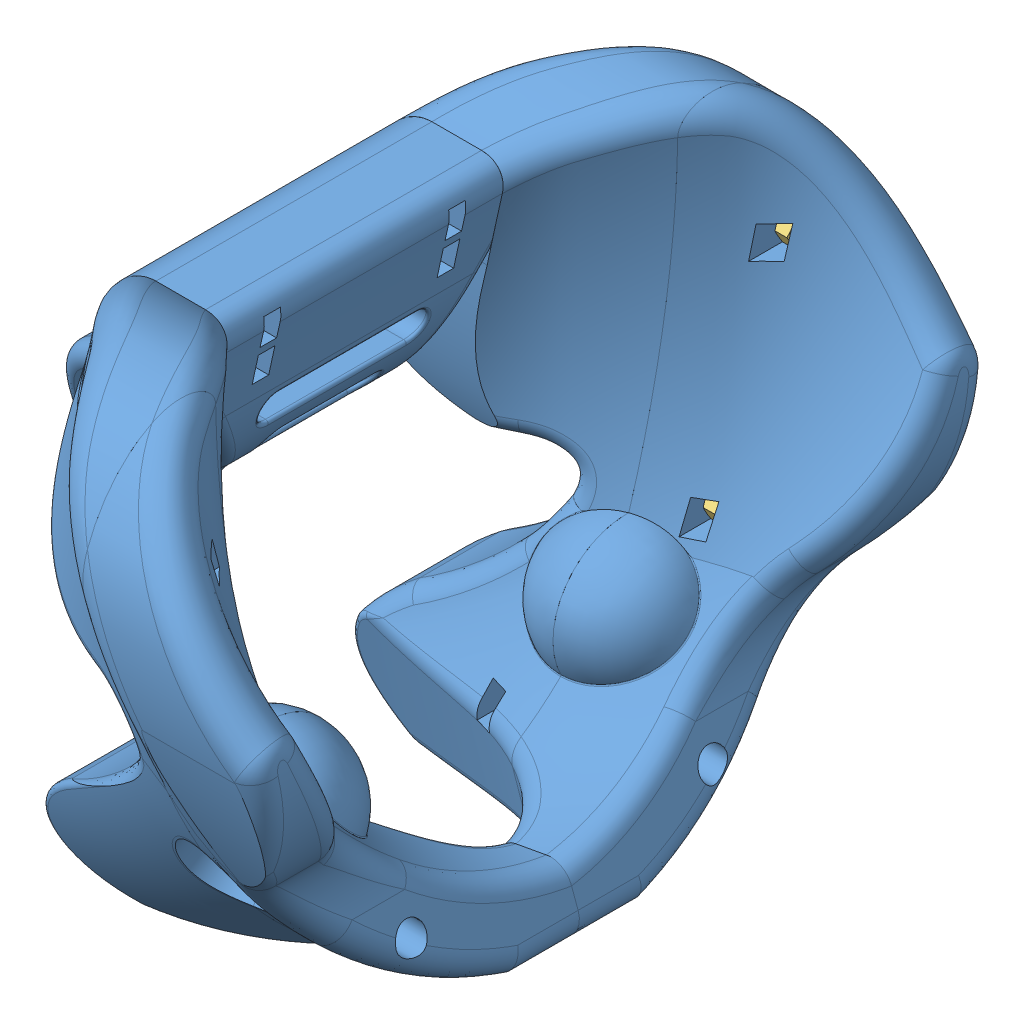
SolidWorks assembly 02_03_Pelvis_Assembly, configuration Default. Lengths in mm.
Overall size (197.88 220.17 282.18).
23 component instances, 3 part files, 55 mates.
Components (placement in the parent):
- 02_01_Pelvis-1: 02_01_Pelvis [Default] at origin size (197.88 220.17 282.18)
- 91239A330_CLASS 10.9 STL BUTTON-HEAD SOCKET CAP SCREW-1: 91239A330_CLASS 10.9 STL BUTTON-HEAD SOCKET CAP SCREW [91239A330] at (-121.884 56.6312 66.8) size (10.5 10.5 38.95)
- 91239A330_CLASS 10.9 STL BUTTON-HEAD SOCKET CAP SCREW-2: 91239A330_CLASS 10.9 STL BUTTON-HEAD SOCKET CAP SCREW [91239A330] at (-104.3146 69.6752 66.8) x (0.987351 0.158553 0) z (0 0 1) size (10.5 10.5 38.95)
- 91239A330_CLASS 10.9 STL BUTTON-HEAD SOCKET CAP SCREW-4: 91239A330_CLASS 10.9 STL BUTTON-HEAD SOCKET CAP SCREW [91239A330] at (-121.884 56.6312 -66.8) x (-0.34202 0.939693 0) z (0 0 -1) size (10.5 10.5 38.95)
- 91239A330_CLASS 10.9 STL BUTTON-HEAD SOCKET CAP SCREW-6: 91239A330_CLASS 10.9 STL BUTTON-HEAD SOCKET CAP SCREW [91239A330] at (-104.3146 69.6752 -66.8) x (-0.5 0.866025 0) z (0 0 -1) size (10.5 10.5 38.95)
- 91239A330_CLASS 10.9 STL BUTTON-HEAD SOCKET CAP SCREW-8: 91239A330_CLASS 10.9 STL BUTTON-HEAD SOCKET CAP SCREW [91239A330] at (-77.844 52.8275 -110.8479) x (0 0 1) z (-1 0 0) size (10.5 10.5 38.95)
- 91239A330_CLASS 10.9 STL BUTTON-HEAD SOCKET CAP SCREW-10: 91239A330_CLASS 10.9 STL BUTTON-HEAD SOCKET CAP SCREW [91239A330] at (-77.844 52.8275 110.8479) x (0 0 1) z (-1 0 0) size (10.5 10.5 38.95)
- 91239A330_CLASS 10.9 STL BUTTON-HEAD SOCKET CAP SCREW-12: 91239A330_CLASS 10.9 STL BUTTON-HEAD SOCKET CAP SCREW [91239A330] at (-77.844 -21.0136 84.8541) x (0 0 1) z (-1 0 0) size (10.5 10.5 38.95)
- 91239A330_CLASS 10.9 STL BUTTON-HEAD SOCKET CAP SCREW-14: 91239A330_CLASS 10.9 STL BUTTON-HEAD SOCKET CAP SCREW [91239A330] at (-77.844 -21.0136 -84.8541) x (0 0 1) z (-1 0 0) size (10.5 10.5 38.95)
- 91239A330_CLASS 10.9 STL BUTTON-HEAD SOCKET CAP SCREW-16: 91239A330_CLASS 10.9 STL BUTTON-HEAD SOCKET CAP SCREW [91239A330] at (-44.244 -75.4386 54.7323) x (0 0.171049 -0.985262) z (1 0 0) size (10.5 10.5 38.95)
- 91239A330_CLASS 10.9 STL BUTTON-HEAD SOCKET CAP SCREW-18: 91239A330_CLASS 10.9 STL BUTTON-HEAD SOCKET CAP SCREW [91239A330] at (-44.244 -75.4386 -54.7323) x (0 0 -1) z (1 0 0) size (10.5 10.5 38.95)
- 91239A330_CLASS 10.9 STL BUTTON-HEAD SOCKET CAP SCREW-20: 91239A330_CLASS 10.9 STL BUTTON-HEAD SOCKET CAP SCREW [91239A330] at (-30.2115 -92.3012 16.8) x (0.985697 -0.168526 0) z (0 0 1) size (10.5 10.5 38.95)
- 94645A205_HIGH-STRENGTH STEEL NYLON-INSERT LOCKNUT-1: 94645A205_HIGH-STRENGTH STEEL NYLON-INSERT LOCKNUT [94645A205] at (-47.544 52.8275 110.8479) x (0 -0.5 -0.866025) z (0 -0.866025 0.5) size (10 6.41 11.55)
- 94645A205_HIGH-STRENGTH STEEL NYLON-INSERT LOCKNUT-2: 94645A205_HIGH-STRENGTH STEEL NYLON-INSERT LOCKNUT [94645A205] at (-47.544 52.8275 -110.8479) x (0 -0.5 -0.866025) z (0 -0.866025 0.5) size (10 6.41 11.55)
- 94645A205_HIGH-STRENGTH STEEL NYLON-INSERT LOCKNUT-4: 94645A205_HIGH-STRENGTH STEEL NYLON-INSERT LOCKNUT [94645A205] at (-47.544 -21.0136 -84.8541) x (0 -0.5 -0.866025) z (0 -0.866025 0.5) size (10 6.41 11.55)
- 94645A205_HIGH-STRENGTH STEEL NYLON-INSERT LOCKNUT-6: 94645A205_HIGH-STRENGTH STEEL NYLON-INSERT LOCKNUT [94645A205] at (-47.544 -21.0136 84.8541) x (0 -0.5 -0.866025) z (0 -0.866025 0.5) size (10 6.41 11.55)
- 94645A205_HIGH-STRENGTH STEEL NYLON-INSERT LOCKNUT-8: 94645A205_HIGH-STRENGTH STEEL NYLON-INSERT LOCKNUT [94645A205] at (-74.544 -75.4386 -54.7323) x (0 -0.5 0.866025) z (0 -0.866025 -0.5) size (10 6.41 11.55)
- 94645A205_HIGH-STRENGTH STEEL NYLON-INSERT LOCKNUT-10: 94645A205_HIGH-STRENGTH STEEL NYLON-INSERT LOCKNUT [94645A205] at (-74.544 -75.4386 54.7323) x (0 -0.5 0.866025) z (0 -0.866025 -0.5) size (10 6.41 11.55)
- 94645A205_HIGH-STRENGTH STEEL NYLON-INSERT LOCKNUT-12: 94645A205_HIGH-STRENGTH STEEL NYLON-INSERT LOCKNUT [94645A205] at (-30.2115 -92.3012 -13.5) x (-0.866025 -0.5 0) z (0.5 -0.866025 0) size (10 6.41 11.55)
- 94645A205_HIGH-STRENGTH STEEL NYLON-INSERT LOCKNUT-14: 94645A205_HIGH-STRENGTH STEEL NYLON-INSERT LOCKNUT [94645A205] at (-104.3146 69.6752 36.5) x (-0.866025 -0.5 0) z (0.5 -0.866025 0) size (10 6.41 11.55)
- 94645A205_HIGH-STRENGTH STEEL NYLON-INSERT LOCKNUT-16: 94645A205_HIGH-STRENGTH STEEL NYLON-INSERT LOCKNUT [94645A205] at (-121.884 56.6312 36.5) x (-0.866025 -0.5 0) z (0.5 -0.866025 0) size (10 6.41 11.55)
- 94645A205_HIGH-STRENGTH STEEL NYLON-INSERT LOCKNUT-18: 94645A205_HIGH-STRENGTH STEEL NYLON-INSERT LOCKNUT [94645A205] at (-104.3146 69.6752 -36.5) x (0.866025 -0.5 0) z (-0.5 -0.866025 0) size (10 6.41 11.55)
- 94645A205_HIGH-STRENGTH STEEL NYLON-INSERT LOCKNUT-20: 94645A205_HIGH-STRENGTH STEEL NYLON-INSERT LOCKNUT [94645A205] at (-121.884 56.6312 -36.5) x (0.866025 -0.5 0) z (-0.5 -0.866025 0) size (10 6.41 11.55)
Mates (geometry in assembly coordinates):
- Concentric1: concentric aligned: cylinder of 02_01_Pelvis-1 through (-121.884 56.6312 143.5354) axis (0 0 -1) radius 3.2; cylinder of 91239A330_CLASS 10.9 STL BUTTON-HEAD SOCKET CAP SCREW-1 through (-121.884 56.6312 28.5) axis (0 0 -1) radius 3
- Coincident1: coincident anti-aligned: plane of 02_01_Pelvis-1 through (-121.884 56.6312 63.5) normal (0 0 1); plane of 91239A330_CLASS 10.9 STL BUTTON-HEAD SOCKET CAP SCREW-1 through (-121.884 51.3812 63.5) normal (0 0 -1)
- Concentric2: concentric aligned: cylinder of 02_01_Pelvis-1 through (-104.3146 69.6752 143.5354) axis (0 0 -1) radius 5.375; cylinder of 91239A330_CLASS 10.9 STL BUTTON-HEAD SOCKET CAP SCREW-2 through (-104.3146 69.6752 28.5) axis (0 0 -1) radius 3
- Coincident2: coincident anti-aligned: plane of 02_01_Pelvis-1 through (-104.3146 69.6752 63.5) normal (0 0 1); plane of 91239A330_CLASS 10.9 STL BUTTON-HEAD SOCKET CAP SCREW-2 through (-103.4822 64.4916 63.5) normal (0 0 -1)
- Concentric3: concentric aligned: cylinder of 02_01_Pelvis-1 through (-121.884 56.6312 -143.5354) axis (0 0 1) radius 5.375; cylinder of 91239A330_CLASS 10.9 STL BUTTON-HEAD SOCKET CAP SCREW-4 through (-121.884 56.6312 -28.5) axis (0 0 1) radius 3
- Coincident3: coincident anti-aligned: circle of 02_01_Pelvis-1; plane of 91239A330_CLASS 10.9 STL BUTTON-HEAD SOCKET CAP SCREW-4 through (-126.8174 54.8356 -63.5) normal (0 0 1)
- Concentric4: concentric aligned: cylinder of 02_01_Pelvis-1 through (-104.3146 69.6752 -143.5354) axis (0 0 1) radius 5.375; cylinder of 91239A330_CLASS 10.9 STL BUTTON-HEAD SOCKET CAP SCREW-6 through (-104.3146 69.6752 -28.5) axis (0 0 1) radius 3
- Coincident4: coincident anti-aligned: plane of 02_01_Pelvis-1 through (-104.3146 69.6752 -63.5) normal (0 0 -1); plane of 91239A330_CLASS 10.9 STL BUTTON-HEAD SOCKET CAP SCREW-6 through (-108.8612 67.0502 -63.5) normal (0 0 1)
- Concentric5: concentric aligned: cylinder of 02_01_Pelvis-1 through (-187.4808 52.8275 -110.8479) axis (1 0 0) radius 5.375; cylinder of 91239A330_CLASS 10.9 STL BUTTON-HEAD SOCKET CAP SCREW-8 through (-39.544 52.8275 -110.8479) axis (1 0 0) radius 3
- Coincident5: coincident anti-aligned: plane of 02_01_Pelvis-1 through (-74.544 52.8275 -110.8479) normal (-1 0 0); plane of 91239A330_CLASS 10.9 STL BUTTON-HEAD SOCKET CAP SCREW-8 through (-74.544 47.5775 -110.8479) normal (1 0 0)
- Concentric6: concentric aligned: cylinder of 02_01_Pelvis-1 through (-187.4808 52.8275 110.8479) axis (1 0 0) radius 5.375; cylinder of 91239A330_CLASS 10.9 STL BUTTON-HEAD SOCKET CAP SCREW-10 through (-39.544 52.8275 110.8479) axis (1 0 0) radius 3
- Coincident6: coincident anti-aligned: plane of 02_01_Pelvis-1 through (-74.544 52.8275 110.8479) normal (-1 0 0); plane of 91239A330_CLASS 10.9 STL BUTTON-HEAD SOCKET CAP SCREW-10 through (-74.544 47.5775 110.8479) normal (1 0 0)
- Concentric7: concentric aligned: cylinder of 02_01_Pelvis-1 through (-187.4808 -21.0136 84.8541) axis (1 0 0) radius 5.375; cylinder of 91239A330_CLASS 10.9 STL BUTTON-HEAD SOCKET CAP SCREW-12 through (-39.544 -21.0136 84.8541) axis (1 0 0) radius 3
- Coincident7: coincident anti-aligned: plane of 02_01_Pelvis-1 through (-74.544 -21.0136 84.8541) normal (-1 0 0); plane of 91239A330_CLASS 10.9 STL BUTTON-HEAD SOCKET CAP SCREW-12 through (-74.544 -26.2636 84.8541) normal (1 0 0)
- Concentric8: concentric aligned: cylinder of 02_01_Pelvis-1 through (-187.4808 -21.0136 -84.8541) axis (1 0 0) radius 5.375; cylinder of 91239A330_CLASS 10.9 STL BUTTON-HEAD SOCKET CAP SCREW-14 through (-39.544 -21.0136 -84.8541) axis (1 0 0) radius 3
- Coincident8: coincident anti-aligned: plane of 02_01_Pelvis-1 through (-74.544 -21.0136 -84.8541) normal (-1 0 0); plane of 91239A330_CLASS 10.9 STL BUTTON-HEAD SOCKET CAP SCREW-14 through (-74.544 -26.2636 -84.8541) normal (1 0 0)
- Concentric9: concentric aligned: cylinder of 02_01_Pelvis-1 through (18.4173 -75.4386 54.7323) axis (-1 0 0) radius 5.375; cylinder of 91239A330_CLASS 10.9 STL BUTTON-HEAD SOCKET CAP SCREW-16 through (-82.544 -75.4386 54.7323) axis (-1 0 0) radius 3
- Coincident9: coincident anti-aligned: plane of 02_01_Pelvis-1 through (-47.544 -75.4386 54.7323) normal (1 0 0); plane of 91239A330_CLASS 10.9 STL BUTTON-HEAD SOCKET CAP SCREW-16 through (-47.544 -80.6112 53.8343) normal (-1 0 0)
- Concentric10: concentric aligned: cylinder of 02_01_Pelvis-1 through (18.4173 -75.4386 -54.7323) axis (-1 0 0) radius 5.375; cylinder of 91239A330_CLASS 10.9 STL BUTTON-HEAD SOCKET CAP SCREW-18 through (-82.544 -75.4386 -54.7323) axis (-1 0 0) radius 3
- Coincident10: coincident anti-aligned: plane of 02_01_Pelvis-1 through (-47.544 -75.4386 -54.7323) normal (1 0 0); plane of 91239A330_CLASS 10.9 STL BUTTON-HEAD SOCKET CAP SCREW-18 through (-47.544 -80.6886 -54.7323) normal (-1 0 0)
- Concentric11: concentric aligned: cylinder of 02_01_Pelvis-1 through (-30.2115 -92.3012 143.5354) axis (0 0 -1) radius 5.375; cylinder of 91239A330_CLASS 10.9 STL BUTTON-HEAD SOCKET CAP SCREW-20 through (-30.2115 -92.3012 -21.5) axis (0 0 -1) radius 3
- Coincident11: coincident anti-aligned: plane of 02_01_Pelvis-1 through (0 0 13.5) normal (0 0 1); plane of 91239A330_CLASS 10.9 STL BUTTON-HEAD SOCKET CAP SCREW-20 through (-31.0962 -97.4761 13.5) normal (0 0 -1)
- Concentric12: concentric aligned: circle of 02_01_Pelvis-1; circle of 94645A205_HIGH-STRENGTH STEEL NYLON-INSERT LOCKNUT-1
- Coincident12: coincident anti-aligned: plane of 02_01_Pelvis-1 through (-47.544 0 0) normal (1 0 0); plane of 94645A205_HIGH-STRENGTH STEEL NYLON-INSERT LOCKNUT-1 through (-47.544 52.8275 105.0744) normal (-1 0 0)
- Parallel1: parallel anti-aligned: plane of 02_01_Pelvis-1 through (-41.044 57.9775 107.8746) normal (0 -1 0); plane of 94645A205_HIGH-STRENGTH STEEL NYLON-INSERT LOCKNUT-1 through (-41.544 57.8275 107.9612) normal (0 1 0)
- Concentric13: concentric anti-aligned: circle of 02_01_Pelvis-1; circle of 94645A205_HIGH-STRENGTH STEEL NYLON-INSERT LOCKNUT-2
- Coincident14: coincident anti-aligned: plane of 02_01_Pelvis-1 through (-47.544 0 0) normal (1 0 0); plane of 94645A205_HIGH-STRENGTH STEEL NYLON-INSERT LOCKNUT-2 through (-47.544 52.8275 -116.6214) normal (-1 0 0)
- Parallel2: parallel anti-aligned: plane of 02_01_Pelvis-1 through (-41.044 57.9775 -107.8746) normal (0 -1 0); plane of 94645A205_HIGH-STRENGTH STEEL NYLON-INSERT LOCKNUT-2 through (-41.544 57.8275 -113.7347) normal (0 1 0)
- Concentric14: concentric anti-aligned: circle of 02_01_Pelvis-1; circle of 94645A205_HIGH-STRENGTH STEEL NYLON-INSERT LOCKNUT-4
- Coincident15: coincident anti-aligned: plane of 02_01_Pelvis-1 through (-47.544 0 0) normal (1 0 0); plane of 94645A205_HIGH-STRENGTH STEEL NYLON-INSERT LOCKNUT-4 through (-47.544 -21.0136 -90.6276) normal (-1 0 0)
- Parallel3: parallel anti-aligned: plane of 02_01_Pelvis-1 through (-41.044 -15.8636 -81.8808) normal (0 -1 0); plane of 94645A205_HIGH-STRENGTH STEEL NYLON-INSERT LOCKNUT-4 through (-41.544 -16.0136 -87.7409) normal (0 1 0)
- Concentric15: concentric aligned: circle of 02_01_Pelvis-1; circle of 94645A205_HIGH-STRENGTH STEEL NYLON-INSERT LOCKNUT-6
- Coincident16: coincident anti-aligned: plane of 02_01_Pelvis-1 through (-47.544 0 0) normal (1 0 0); plane of 94645A205_HIGH-STRENGTH STEEL NYLON-INSERT LOCKNUT-6 through (-47.544 -21.0136 79.0806) normal (-1 0 0)
- Parallel4: parallel anti-aligned: plane of 02_01_Pelvis-1 through (-41.044 -15.8636 81.8808) normal (0 -1 0); plane of 94645A205_HIGH-STRENGTH STEEL NYLON-INSERT LOCKNUT-6 through (-41.544 -16.0136 81.9674) normal (0 1 0)
- Concentric16: concentric anti-aligned: circle of 02_01_Pelvis-1; circle of 94645A205_HIGH-STRENGTH STEEL NYLON-INSERT LOCKNUT-8
- Coincident17: coincident anti-aligned: plane of 02_01_Pelvis-1 through (-74.544 0 0) normal (-1 0 0); plane of 94645A205_HIGH-STRENGTH STEEL NYLON-INSERT LOCKNUT-8 through (-74.544 -75.4386 -48.9588) normal (1 0 0)
- Parallel5: parallel anti-aligned: plane of 02_01_Pelvis-1 through (-81.044 -70.2886 -51.7589) normal (0 -1 0); plane of 94645A205_HIGH-STRENGTH STEEL NYLON-INSERT LOCKNUT-8 through (-80.544 -70.4386 -51.8455) normal (0 1 0)
- Concentric17: concentric aligned: circle of 02_01_Pelvis-1; circle of 94645A205_HIGH-STRENGTH STEEL NYLON-INSERT LOCKNUT-10
- Coincident18: coincident anti-aligned: plane of 02_01_Pelvis-1 through (-74.544 0 0) normal (-1 0 0); plane of 94645A205_HIGH-STRENGTH STEEL NYLON-INSERT LOCKNUT-10 through (-74.544 -75.4386 60.5058) normal (1 0 0)
- Parallel6: parallel anti-aligned: plane of 02_01_Pelvis-1 through (-81.044 -70.2886 51.7589) normal (0 -1 0); plane of 94645A205_HIGH-STRENGTH STEEL NYLON-INSERT LOCKNUT-10 through (-80.544 -70.4386 57.619) normal (0 1 0)
- Concentric18: concentric anti-aligned: circle of 02_01_Pelvis-1; circle of 94645A205_HIGH-STRENGTH STEEL NYLON-INSERT LOCKNUT-12
- Coincident19: coincident anti-aligned: plane of 02_01_Pelvis-1 through (0 0 -13.5) normal (0 0 -1); plane of 94645A205_HIGH-STRENGTH STEEL NYLON-INSERT LOCKNUT-12 through (-35.985 -92.3012 -13.5) normal (0 0 1)
- Parallel7: parallel anti-aligned: plane of 02_01_Pelvis-1 through (-33.1848 -87.1512 -143.5354) normal (0 -1 0); plane of 94645A205_HIGH-STRENGTH STEEL NYLON-INSERT LOCKNUT-12 through (-33.0982 -87.3012 -19.5) normal (0 1 0)
- Concentric19: concentric aligned: circle of 02_01_Pelvis-1; circle of 94645A205_HIGH-STRENGTH STEEL NYLON-INSERT LOCKNUT-14
- Coincident20: coincident anti-aligned: plane of 02_01_Pelvis-1 through (0 0 36.5) normal (0 0 -1); plane of 94645A205_HIGH-STRENGTH STEEL NYLON-INSERT LOCKNUT-14 through (-110.0881 69.6752 36.5) normal (0 0 1)
- Parallel8: parallel anti-aligned: plane of 02_01_Pelvis-1 through (-107.2879 74.8252 30.5) normal (0 -1 0); plane of 94645A205_HIGH-STRENGTH STEEL NYLON-INSERT LOCKNUT-14 through (-107.2013 74.6752 30.5) normal (0 1 0)
- Concentric20: concentric aligned: circle of 02_01_Pelvis-1; circle of 94645A205_HIGH-STRENGTH STEEL NYLON-INSERT LOCKNUT-16
- Coincident21: coincident anti-aligned: plane of 02_01_Pelvis-1 through (0 0 36.5) normal (0 0 -1); plane of 94645A205_HIGH-STRENGTH STEEL NYLON-INSERT LOCKNUT-16 through (-127.6575 56.6312 36.5) normal (0 0 1)
- Parallel9: parallel anti-aligned: plane of 02_01_Pelvis-1 through (-124.8574 61.7812 30.5) normal (0 -1 0); plane of 94645A205_HIGH-STRENGTH STEEL NYLON-INSERT LOCKNUT-16 through (-124.7708 61.6312 30.5) normal (0 1 0)
- Concentric21: concentric anti-aligned: circle of 02_01_Pelvis-1; circle of 94645A205_HIGH-STRENGTH STEEL NYLON-INSERT LOCKNUT-18
- Coincident22: coincident anti-aligned: plane of 02_01_Pelvis-1 through (0 0 -36.5) normal (0 0 1); plane of 94645A205_HIGH-STRENGTH STEEL NYLON-INSERT LOCKNUT-18 through (-98.5411 69.6752 -36.5) normal (0 0 -1)
- Parallel10: parallel anti-aligned: plane of 02_01_Pelvis-1 through (-107.2879 74.8252 -30.5) normal (0 -1 0); plane of 94645A205_HIGH-STRENGTH STEEL NYLON-INSERT LOCKNUT-18 through (-101.4278 74.6752 -30.5) normal (0 1 0)
- Concentric22: concentric anti-aligned: circle of 02_01_Pelvis-1; circle of 94645A205_HIGH-STRENGTH STEEL NYLON-INSERT LOCKNUT-20
- Coincident23: coincident anti-aligned: plane of 02_01_Pelvis-1 through (0 0 -36.5) normal (0 0 1); plane of 94645A205_HIGH-STRENGTH STEEL NYLON-INSERT LOCKNUT-20 through (-116.1105 56.6312 -36.5) normal (0 0 -1)
- Parallel11: parallel anti-aligned: plane of 02_01_Pelvis-1 through (-124.8574 61.7812 -30.5) normal (0 -1 0); plane of 94645A205_HIGH-STRENGTH STEEL NYLON-INSERT LOCKNUT-20 through (-118.9973 61.6312 -30.5) normal (0 1 0)
